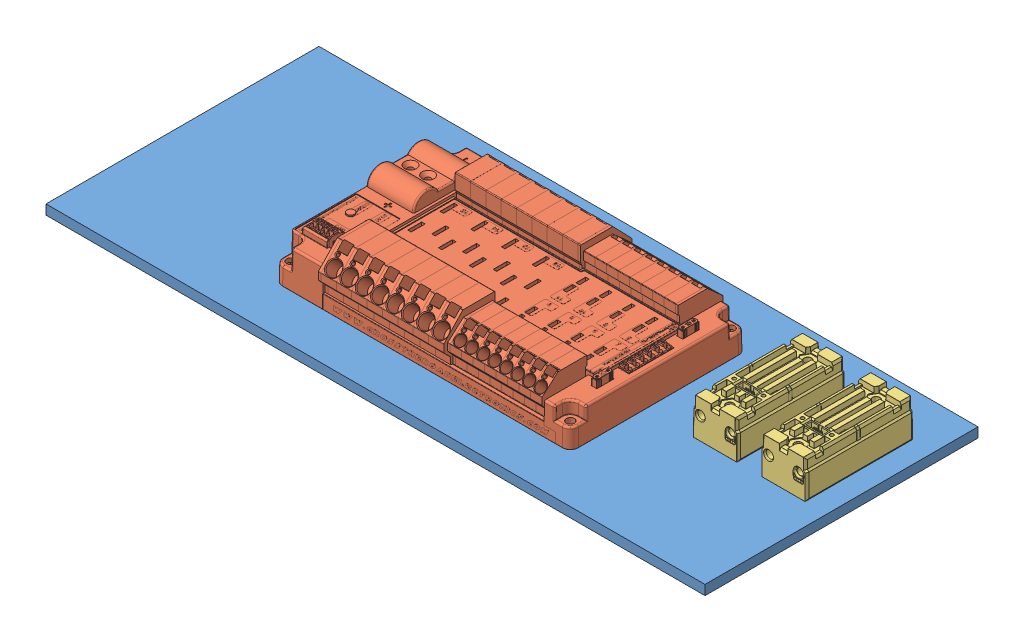
SolidWorks assembly top board with location dimensions, configuration Default. Lengths in mm.
Overall size (429.26 42.5 177.8).
5 component instances, 4 part files, 12 mates.
Components (placement in the parent):
- board 2-1: board 2 [Default] at (-361.6521 10.7419 157.0266) size (429.26 6.35 177.8)
- PDP-1: PDP [Default] at (-142.6393 23.7721 69.1088) size (192.68 36.15 120.93)
- Breaker-1: Breaker [Default] at (-309.1683 21.9179 48.6004) (suppressed, hidden)
- Speed Controller-1: Speed Controller [Default] at (-5.0221 32.9294 42.806) x (1 0 0) z (0 -1 0) size (30.12 70.11 24.39)
- Speed Controller-2: Speed Controller [Default] at (39.4279 32.9294 42.806) x (1 0 0) z (0 -1 0) size (30.12 70.11 24.39)
Mates (geometry in assembly coordinates):
- Coincident1: coincident anti-aligned: plane of board 2-1 through (-361.6521 17.0919 157.0266) normal (0 1 0); plane of PDP-1 through (-50.6151 17.0919 126.5128) normal (0 -1 0)
- Distance1: distance = 127 mm aligned: plane of PDP-1 through (-234.6521 47.6337 106.9566) normal (-1 0 0); plane of board 2-1 through (-361.6521 17.0919 157.0266) normal (-1 0 0)
- Coincident4: coincident anti-aligned: plane of board 2-1 through (-361.6521 17.0919 157.0266) normal (0 1 0); plane of Breaker-1 through (-277.6813 17.0919 66.0859) normal (0 -1 0)
- Coincident5: coincident anti-aligned: plane of board 2-1 through (-361.6521 17.0919 157.0266) normal (0 1 0); plane of Speed Controller-1 through (10.0402 17.0919 7.881) normal (0 -1 0)
- Coincident6: coincident anti-aligned: plane of board 2-1 through (-361.6521 17.0919 157.0266) normal (0 1 0); plane of Speed Controller-2 through (54.4902 17.0919 7.881) normal (0 -1 0)
- Distance2: distance = 46.99 mm aligned: plane of PDP-1 through (-227.6521 47.6337 110.0366) normal (0 0 1); plane of board 2-1 through (-361.6521 17.0919 157.0266) normal (0 0 1)
- Distance3: distance = 101.6 mm aligned: plane of Speed Controller-2 through (38.3979 39.5794 55.4266) normal (0 0 1); plane of board 2-1 through (-361.6521 17.0919 157.0266) normal (0 0 1)
- Distance4: distance = 101.6 mm aligned: plane of Speed Controller-1 through (-6.0521 39.5794 55.4266) normal (0 0 1); plane of board 2-1 through (-361.6521 17.0919 157.0266) normal (0 0 1)
- Distance6: distance = 25.4 mm aligned: plane of board 2-1 through (67.6079 17.0919 157.0266) normal (1 0 0); plane of Speed Controller-2 through (42.2079 39.5794 55.0266) normal (1 0 0)
- Distance7: distance = 69.85 mm: plane of Speed Controller-1 through (-2.2421 39.5794 55.0266) normal (1 0 0); line of board 2-1 through (67.6079 17.0919 157.0266) axis (0 0 -1)
- Distance8: distance = 50.8 mm aligned: plane of Breaker-1 through (-310.8521 52.8909 66.3804) normal (-1 0 0); plane of board 2-1 through (-361.6521 17.0919 157.0266) normal (-1 0 0)
- Distance9: distance = 88.9 mm anti-aligned: plane of Breaker-1 through (-283.8012 33.6527 68.1266) normal (0 0 -1); plane of board 2-1 through (-361.6521 17.0919 157.0266) normal (0 0 1)
